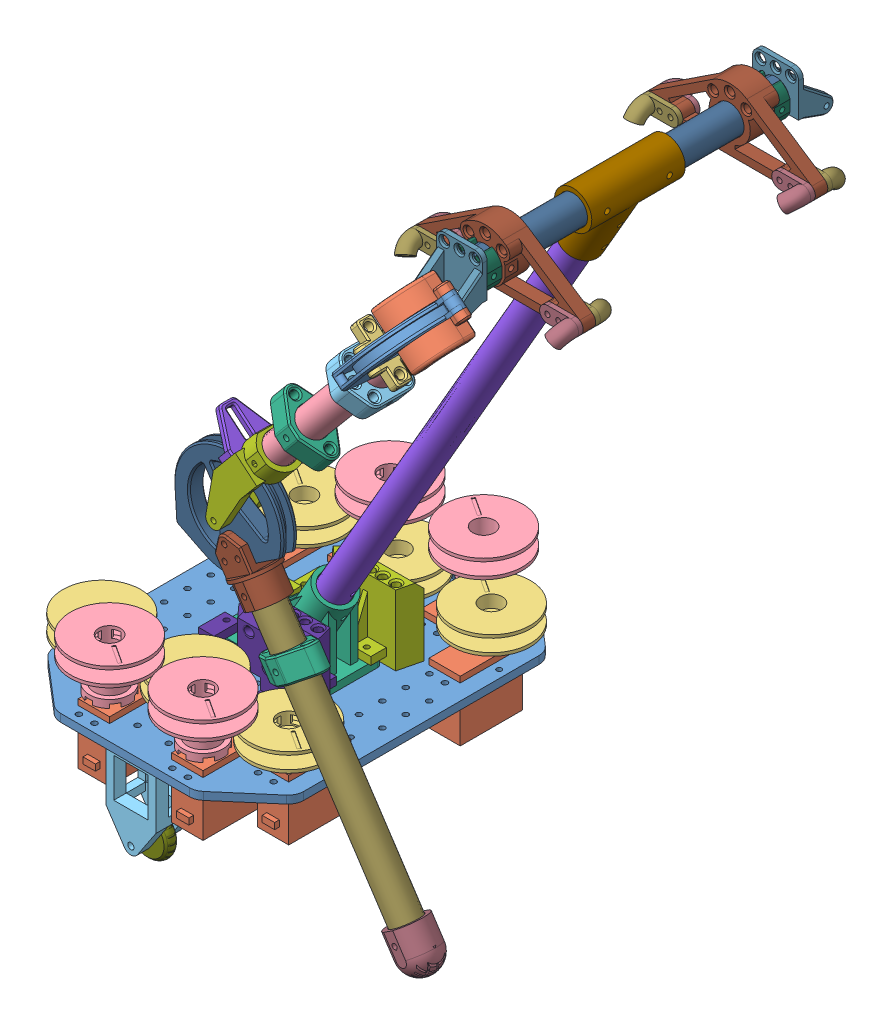
SolidWorks assembly limk_all, configuration ﾃﾞﾌｫﾙﾄ. Lengths in mm.
Overall size (358.86 478.63 301.97).
78 component instances, 31 part files, 6 mates.
Components (placement in the parent):
- link_root-1: link_root [ﾃﾞﾌｫﾙﾄ] at origin size (358.86 458.12 257.01)
  - base_motor-1: base_motor [ﾃﾞﾌｫﾙﾄ] at origin size (192.73 114.3 257.01)
    - base-1: base [ﾃﾞﾌｫﾙﾄ] at origin size (160.1 5 220.2)
    - motor-1: motor [ﾃﾞﾌｫﾙﾄ] at (0 -30 -30.05) x (0 0 1) z (-1 0 0) size (73.36 59.5 70.97)
      - FB5311M-1: FB5311M [ﾃﾞﾌｫﾙﾄ] at origin size (54 44.25 20.1)
      - servo_horn_short-1: servo_horn_short [ﾃﾞﾌｫﾙﾄ] at (-10 42.5 0) x (-0.837169 0 -0.546944) z (0 1 0) size (50 57.04 17)
    - motor-2: motor [ﾃﾞﾌｫﾙﾄ] at (-60 -30 -30.05) x (0 0 1) z (-1 0 0) size (73.36 59.5 70.97)
      - FB5311M-1: FB5311M [ﾃﾞﾌｫﾙﾄ] at origin size (54 44.25 20.1)
      - servo_horn_short-1: servo_horn_short [ﾃﾞﾌｫﾙﾄ] at (-10 42.5 0) x (-0.837169 0 -0.546944) z (0 1 0) size (50 57.04 17)
    - motor-3: motor [ﾃﾞﾌｫﾙﾄ] at (60 -30 -30.05) x (0 0 1) z (-1 0 0) size (73.36 59.5 70.97)
      - FB5311M-1: FB5311M [ﾃﾞﾌｫﾙﾄ] at origin size (54 44.25 20.1)
      - servo_horn_short-1: servo_horn_short [ﾃﾞﾌｫﾙﾄ] at (-10 42.5 0) x (-0.837169 0 -0.546944) z (0 1 0) size (50 57.04 17)
    - motor_long-6: motor_long [ﾃﾞﾌｫﾙﾄ] at (-30 -30 -55.05) x (0 0 1) z (-1 0 0) size (73.92 74.5 73.92) (flexible)
      - FB5311M-1: FB5311M [ﾃﾞﾌｫﾙﾄ] at origin size (54 44.25 20.1)
      - servo_horn_long-1: servo_horn_long [ﾃﾞﾌｫﾙﾄ] at (-10 42.5 0) x (0.789041 0 0.61434) z (0 1 0) size (50 57.04 32)
    - motor_long-5: motor_long [ﾃﾞﾌｫﾙﾄ] at (30 -30 -55.05) x (0 0 1) z (-1 0 0) size (75.45 74.5 73.44)
      - FB5311M-1: FB5311M [ﾃﾞﾌｫﾙﾄ] at origin size (54 44.25 20.1)
      - servo_horn_long-1: servo_horn_long [ﾃﾞﾌｫﾙﾄ] at (-10 42.5 0) x (-0.837169 0 -0.546944) z (0 1 0) size (50 57.04 32)
    - wheel_support-1: wheel_support [ﾃﾞﾌｫﾙﾄ] at (0 0 -67.1) x (0 0 1) z (0 -1 0) size (28.5 32 55)
    - connector_45-1: connector_45 [ﾃﾞﾌｫﾙﾄ] at (0 10 25) x (0 0 1) z (0 1 0) size (40 70.39 54.3)
    - motor-4: motor [ﾃﾞﾌｫﾙﾄ] at (-60 -30 80.05) x (0 0 -1) z (1 0 0) size (73.36 59.5 70.97)
      - FB5311M-1: FB5311M [ﾃﾞﾌｫﾙﾄ] at origin size (54 44.25 20.1)
      - servo_horn_short-1: servo_horn_short [ﾃﾞﾌｫﾙﾄ] at (-10 42.5 0) x (-0.837169 0 -0.546944) z (0 1 0) size (50 57.04 17)
    - motor-5: motor [ﾃﾞﾌｫﾙﾄ] at (0 -30 80.05) x (0 0 -1) z (1 0 0) size (73.36 59.5 70.97)
      - FB5311M-1: FB5311M [ﾃﾞﾌｫﾙﾄ] at origin size (54 44.25 20.1)
      - servo_horn_short-1: servo_horn_short [ﾃﾞﾌｫﾙﾄ] at (-10 42.5 0) x (-0.837169 0 -0.546944) z (0 1 0) size (50 57.04 17)
    - motor-6: motor [ﾃﾞﾌｫﾙﾄ] at (60 -30 80.05) x (0 0 -1) z (1 0 0) size (73.36 59.5 70.97)
      - FB5311M-1: FB5311M [ﾃﾞﾌｫﾙﾄ] at origin size (54 44.25 20.1)
      - servo_horn_short-1: servo_horn_short [ﾃﾞﾌｫﾙﾄ] at (-10 42.5 0) x (-0.837169 0 -0.546944) z (0 1 0) size (50 57.04 17)
    - motor_long-7: motor_long [ﾃﾞﾌｫﾙﾄ] at (-30 -30 105.05) x (0 0 -1) z (1 0 0) size (75.45 74.5 73.44)
      - FB5311M-1: FB5311M [ﾃﾞﾌｫﾙﾄ] at origin size (54 44.25 20.1)
      - servo_horn_long-1: servo_horn_long [ﾃﾞﾌｫﾙﾄ] at (-10 42.5 0) x (-0.837169 0 -0.546944) z (0 1 0) size (50 57.04 32)
    - motor_long-8: motor_long [ﾃﾞﾌｫﾙﾄ] at (30 -30 105.05) x (0 0 -1) z (1 0 0) size (75.45 74.5 73.44)
      - FB5311M-1: FB5311M [ﾃﾞﾌｫﾙﾄ] at origin size (54 44.25 20.1)
      - servo_horn_long-1: servo_horn_long [ﾃﾞﾌｫﾙﾄ] at (-10 42.5 0) x (-0.837169 0 -0.546944) z (0 1 0) size (50 57.04 32)
    - wheel_support-2: wheel_support [ﾃﾞﾌｫﾙﾄ] at (0 0 117.1) x (0 0 -1) z (0 -1 0) size (28.5 32 55)
  - root_connector_loft-1: root_connector_loft [ﾃﾞﾌｫﾙﾄ] at (0 5 -10) x (0 0 -1) z (1 0 0) size (39 45 81.16)
  - pipe_body-1: pipe_body [body] at (202.5 360.7403 25) x (-0.866025 0.5 0) z (-0.5 -0.866025 0) size (18 18 400)
  - connector_T-1: connector_T [ﾃﾞﾌｫﾙﾄ] at (207.5 369.4005 25) x (-0.5 -0.866025 0) z (-0.866025 0.5 0) size (62 60 24)
  - pipe_shoulder-1: pipe_shoulder [ﾃﾞﾌｫﾙﾄ] at (207.5 369.4005 -75) size (18 18 200)
  - assem_shoulder-3: assem_shoulder [left] at (207.5 369.4005 -45.5) x (-1 0 0) z (0 0 -1) size (110 42.64 39.98)
    - wire_root_curve-1: wire_root_curve [ﾃﾞﾌｫﾙﾄ] at origin size (110 40 16)
    - wire_root_curve_support-1: wire_root_curve_support [ﾃﾞﾌｫﾙﾄ] at (-50 -15 11) size (25 12.64 15.99)
    - wire_root_curve_support_mirror-1: wire_root_curve_support_mirror [ﾃﾞﾌｫﾙﾄ] at (50 -15 5) x (-1 0 0) z (0 0 -1) size (25 12.64 15.99)
    - wire_root_curve_support-2: wire_root_curve_support [45] at (50 -15 -3) x (-1 0 0) z (0 0 -1) size (25 12.5 15.99)
    - wire_root_curve_support_mirror-2: wire_root_curve_support_mirror [76] at (-50 -15 3) size (25 12.37 15.99)
  - assem_shoulder-2: assem_shoulder [ﾃﾞﾌｫﾙﾄ] at (207.5 369.4005 95.5) size (110 42.64 39.98)
    - wire_root_curve-1: wire_root_curve [ﾃﾞﾌｫﾙﾄ] at origin size (110 40 16)
    - wire_root_curve_support-1: wire_root_curve_support [ﾃﾞﾌｫﾙﾄ] at (-50 -15 11) size (25 12.64 15.99)
    - wire_root_curve_support_mirror-1: wire_root_curve_support_mirror [ﾃﾞﾌｫﾙﾄ] at (50 -15 5) x (-1 0 0) z (0 0 -1) size (25 12.64 15.99)
    - wire_root_curve_support-2: wire_root_curve_support [76] at (50 -15 -3) x (-1 0 0) z (0 0 -1) size (25 12.37 15.99)
    - wire_root_curve_support_mirror-2: wire_root_curve_support_mirror [45] at (-50 -15 3) size (25 12.5 15.99)
  - shoulder3-1: shoulder3 [ﾃﾞﾌｫﾙﾄ] at (207.5 369.4005 -60) x (1 0 0) z (0 0 -1) size (29.5 33 38)
  - shoulder3-2: shoulder3 [ﾃﾞﾌｫﾙﾄ] at (207.5 369.4005 110) x (-1 0 0) z (0 0 1) size (29.5 33 38)
  - shoulder_patch-1: shoulder_patch [ﾃﾞﾌｫﾙﾄ] at (207.5 369.4005 112.5) size (23.48 22.98 10)
  - shoulder_patch-2: shoulder_patch [ﾃﾞﾌｫﾙﾄ] at (207.5 369.4005 -72.5) size (23.48 22.98 10)
  - wheel-1: wheel [ﾃﾞﾌｫﾙﾄ] at (0 -50 -67.1) x (0.849993 0.526793 0) z (0 0 1) size (27.11 27.11 8)
  - wheel-2: wheel [ﾃﾞﾌｫﾙﾄ] at (0 -50 117.1) x (0.53873 0.842478 0) z (0 0 1) size (27.11 27.11 8)
  - root_connector_loft_mirror-1: root_connector_loft_mirror [ﾃﾞﾌｫﾙﾄ] at (0 5 60) x (0 0 -1) z (1 0 0) size (39 45 81.16)
- link_leg-1: link_leg [ﾃﾞﾌｫﾙﾄ] at (194.6412 335.0823 143.0699) x (0 0.002763 0.999996) z (0.64294 0.765914 -0.002116) size (70.45 52.25 265.64)
  - shoulder_joint_connector-1: shoulder_joint_connector [outer] at origin size (39.7 24.5 59)
  - shoulder_joint_circle-1: shoulder_joint_circle [ﾃﾞﾌｫﾙﾄ] at (19.95 5 26) x (1 0 0) z (0 -1 0) size (40 79.64 10)
  - shoulder_fromknee_middle_curve-1: shoulder_fromknee_middle_curve [mirror] at (18.95 5 58.641) x (0 0 1) z (0 1 0) size (28 28.97 13)
  - shoulder_fromknee_middle_curve-2: shoulder_fromknee_middle_curve [ﾃﾞﾌｫﾙﾄ] at (18.95 -5 58.641) x (0 0 1) z (0 1 0) size (28 28.97 13)
  - shoulder_fromknee_middle-1: shoulder_fromknee_middle [ﾃﾞﾌｫﾙﾄ] at (38.95 5 26) x (1 0 0) z (0 -1 0) size (24 8 13)
  - shoulder_fromknee_middle-2: shoulder_fromknee_middle [ﾃﾞﾌｫﾙﾄ] at (38.95 -5 26) x (-1 0 0) z (0 1 0) size (24 8 13)
  - pipe_leg-1: pipe_leg [ﾃﾞﾌｫﾙﾄ] x (1 0 0) z (0 0 -1) size (18 18 150)
  - wire_end_5_small-1: wire_end_5_small [ﾃﾞﾌｫﾙﾄ] at (0 0 -45) x (0 -1 0) z (0 0 1) size (31 35.94 15)
  - wire_end_small-1: wire_end_small [ﾃﾞﾌｫﾙﾄ] at (0 0 -110) x (0 1 0) z (0 0 1) size (40.5 24.5 15)
  - knee2-1: knee2 [outer] at (0 0 -135) x (-1 0 0) z (0 0 -1) size (28.5 25.58 60)
  - knee_support-1: knee_support [ﾃﾞﾌｫﾙﾄ] at (0 -9 -158) x (-1 0 0) z (0 -1 0) size (28.5 11 23)
- shoulder2-1: shoulder2 [ﾃﾞﾌｫﾙﾄ] at (207.5 365.4005 142.9862) x (1 0 0) z (0 -0.999996 0.002763) size (15 15 20)
- link_foot-1: link_foot [ﾃﾞﾌｫﾙﾄ] at (79.3759 183.7584 138.488) x (0.832391 0.554187 -0.001531) z (0 0.002763 0.999996) size (75 268.41 28.1)
  - knee_joint_circle-1: knee_joint_circle [ﾃﾞﾌｫﾙﾄ] at origin size (75 60.98 10)
  - knee_joint_connector-1: knee_joint_connector [outer] at (-5 -31.1808 5) x (0 0 -1) z (0 1 0) size (28.1 28.1 37.95)
  - pipe_foot-1: pipe_foot [ﾃﾞﾌｫﾙﾄ] at (-5 -31.1808 5) x (0 0 1) z (0 -1 0) size (18 18 190)
  - wire_end_small-1: wire_end_small [ﾃﾞﾌｫﾙﾄ] at (-5 -76.1808 5) x (1 0 0) z (0 1 0) size (40.5 24.5 15)
  - foot_simple-1: foot_simple [ﾃﾞﾌｫﾙﾄ] at (-5 -221.1808 5) x (0 0 -1) z (-1 0 0) size (23.48 27.23 24.5)
Mates (geometry in assembly coordinates):
- 同心円1: concentric: cylinder of link_root-1/shoulder3-2 through (197.75 360.4005 143) axis (-1 0 0) radius 1.65; cylinder of shoulder2-1 through (200 360.4005 143) axis (1 0 0) radius 2.45
- 幅1: width anti-aligned: plane of link_root-1/shoulder3-2 through (197.75 360.4005 143) normal (1 0 0); plane of shoulder2-1 through (217.25 360.4005 143) normal (-1 0 0); plane of link_root-1/shoulder3-2 through (200 345.4213 150.5414) normal (-1 0 0); plane of shoulder2-1 through (215 345.4213 150.5414) normal (1 0 0)
- 同心円2: concentric: cylinder of link_leg-1/shoulder_joint_connector-1 through (207.5 350.3736 133.2777) axis (0 -0.002763 -0.999996) radius 1.65; cylinder of shoulder2-1 through (207.5 350.3799 135.5277) axis (0 0.002763 0.999996) radius 2.45
- 幅2: width anti-aligned: plane of link_leg-1/shoulder_joint_connector-1 through (194.6412 335.1092 152.8199) normal (0 -0.002763 -0.999996); plane of shoulder2-1 through (207.5 350.3736 133.2777) normal (0 0.002763 0.999996); plane of link_leg-1/shoulder_joint_connector-1 through (200 345.4213 150.5414) normal (0 0.002763 0.999996); plane of shoulder2-1 through (200 345.3799 135.5415) normal (0 -0.002763 -0.999996)
- 同心円3: concentric anti-aligned: cylinder of link_leg-1/knee2-1 through (79.3759 183.7923 150.738) axis (0 0.002763 0.999996) radius 1.65; cylinder of link_foot-1/knee_joint_circle-1 through (79.3759 183.786 148.488) axis (0 -0.002763 -0.999996) radius 2.45
- 幅3: width anti-aligned: plane of link_leg-1/knee2-1 through (79.3759 183.7923 150.738) normal (0 -0.002763 -0.999996); plane of link_foot-1/knee_joint_circle-1 through (79.3759 183.7522 136.238) normal (0 0.002763 0.999996); plane of link_leg-1/knee2-1 through (79.3759 183.786 148.488) normal (0 0.002763 0.999996); plane of link_foot-1/knee_joint_circle-1 through (79.3759 183.7584 138.488) normal (0 -0.002763 -0.999996)
